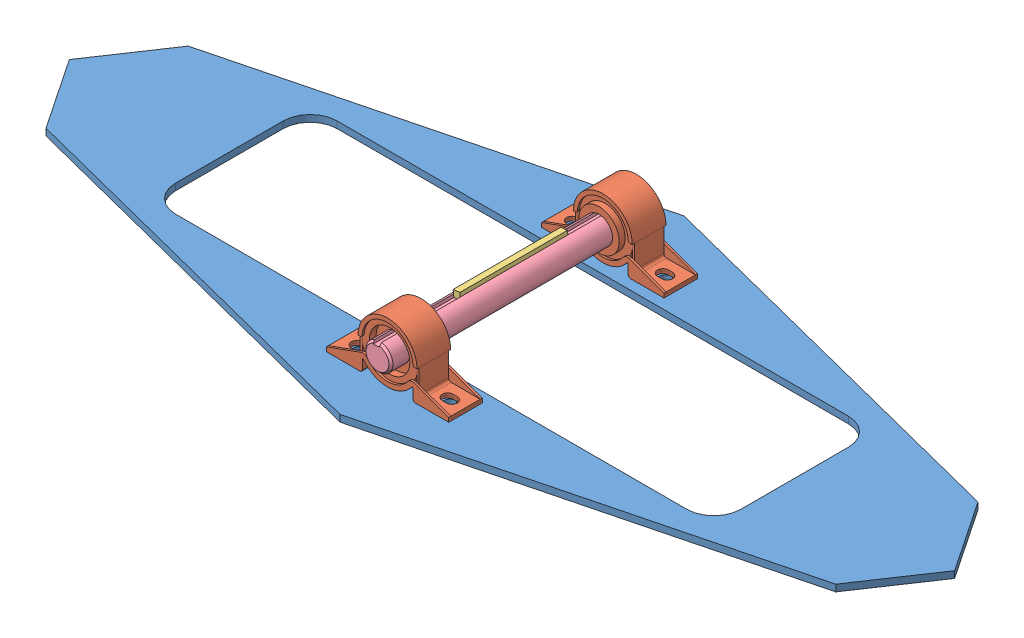
SolidWorks assembly SubAssembly_PendulumMount, configuration Default. Lengths in mm.
Overall size (835.56 62.71 324.57).
5 component instances, 4 part files, 12 mates.
Components (placement in the parent):
- Platform_Octagon_Pend-1: Platform_Octagon_Pend [Default] at origin size (835.56 6.35 324.57)
- 5913K640_LOW-PROFILE MOUNTED BALL BRNG-1: 5913K640_LOW-PROFILE MOUNTED BALL BRNG [5913K64] at (0 31.75 -101.6) size (115.49 56.36 35.32)
- Keystock-1: Keystock [Default] at (-1.2779 44.3855 0) x (0 0 1) z (-0.994925 -0.100619 0) size (101.6 6.35 6.35)
- 1497K281_FULLY KEYED 1045 STEEL DRIVE SHAFT-1: 1497K281_FULLY KEYED 1045 STEEL DRIVE SHAFT [1497K281] at (0 31.75 0) x (0 0 1) z (-0.994925 -0.100619 0) size (254 25.4 25.4)
- 5913K640_LOW-PROFILE MOUNTED BALL BRNG-2: 5913K640_LOW-PROFILE MOUNTED BALL BRNG [5913K64] at (0 31.75 101.6) x (-1 0 0) z (0 0 -1) size (115.49 56.36 35.32)
Mates (geometry in assembly coordinates):
- Coincident5: coincident anti-aligned: plane of Keystock-1 through (2.2005 41.5461 50.8) normal (0.994925 0.100619 0); plane of 1497K281_FULLY KEYED 1045 STEEL DRIVE SHAFT-1 through (1.881 44.705 -127) normal (-0.994925 -0.100619 0)
- Coincident6: coincident anti-aligned: plane of Keystock-1 through (2.2005 41.5461 50.8) normal (0.100619 -0.994925 0); plane of 1497K281_FULLY KEYED 1045 STEEL DRIVE SHAFT-1 through (-4.1173 40.9072 -127) normal (-0.100619 0.994925 0)
- Width2: width anti-aligned: plane of Keystock-1 through (-1.2779 44.3855 -50.8) normal (0 0 -1); plane of Keystock-1 through (-1.2779 44.3855 50.8) normal (0 0 1); plane of 1497K281_FULLY KEYED 1045 STEEL DRIVE SHAFT-1 through (0 31.75 127) normal (0 0 1); plane of 1497K281_FULLY KEYED 1045 STEEL DRIVE SHAFT-1 through (0 31.75 -127) normal (0 0 -1)
- Concentric1: concentric anti-aligned: cylinder of 1497K281_FULLY KEYED 1045 STEEL DRIVE SHAFT-1 through (0 31.75 127) axis (0 0 -1) radius 12.7; cylinder of 5913K640_LOW-PROFILE MOUNTED BALL BRNG-1 through (0 31.75 -109.1406) axis (0 0 1) radius 12.7
- Coincident7: coincident anti-aligned: plane of Platform_Octagon_Pend-1 through (0 3.175 0) normal (0 1 0); plane of 5913K640_LOW-PROFILE MOUNTED BALL BRNG-1 through (-57.7453 3.175 -85.725) normal (0 -1 0)
- Slot1: slot aligned: cylinder of Platform_Octagon_Pend-1 through (-42.8625 -3.175 -101.6) axis (0 1 0) radius 5.1594; cylinder of 5913K640_LOW-PROFILE MOUNTED BALL BRNG-1 through (-40.8781 3.175 -101.6) axis (0 1 0) radius 5.1594; cylinder of 5913K640_LOW-PROFILE MOUNTED BALL BRNG-1 through (-44.8469 3.175 -101.6) axis (0 1 0) radius 5.1594
- Slot2: slot aligned: cylinder of Platform_Octagon_Pend-1 through (42.8625 -3.175 -101.6) axis (0 1 0) radius 5.1594; cylinder of 5913K640_LOW-PROFILE MOUNTED BALL BRNG-1 through (40.8781 3.175 -101.6) axis (0 1 0) radius 5.1594; cylinder of 5913K640_LOW-PROFILE MOUNTED BALL BRNG-1 through (44.8469 3.175 -101.6) axis (0 1 0) radius 5.1594
- Concentric2: concentric aligned: cylinder of 1497K281_FULLY KEYED 1045 STEEL DRIVE SHAFT-1 through (0 31.75 127) axis (0 0 -1) radius 12.7; cylinder of 5913K640_LOW-PROFILE MOUNTED BALL BRNG-2 through (0 31.75 109.1406) axis (0 0 -1) radius 12.7
- Coincident8: coincident anti-aligned: plane of Platform_Octagon_Pend-1 through (0 3.175 0) normal (0 1 0); plane of 5913K640_LOW-PROFILE MOUNTED BALL BRNG-2 through (-26.0572 3.175 85.725) normal (0 -1 0)
- Slot3: slot aligned: cylinder of Platform_Octagon_Pend-1 through (-42.8625 -3.175 101.6) axis (0 1 0) radius 5.1594; cylinder of 5913K640_LOW-PROFILE MOUNTED BALL BRNG-2 through (-40.8781 3.175 101.6) axis (0 1 0) radius 5.1594; cylinder of 5913K640_LOW-PROFILE MOUNTED BALL BRNG-2 through (-44.8469 3.175 101.6) axis (0 1 0) radius 5.1594
- Slot4: slot aligned: cylinder of Platform_Octagon_Pend-1 through (42.8625 -3.175 101.6) axis (0 1 0) radius 5.1594; cylinder of 5913K640_LOW-PROFILE MOUNTED BALL BRNG-2 through (44.8469 3.175 101.6) axis (0 1 0) radius 5.1594; cylinder of 5913K640_LOW-PROFILE MOUNTED BALL BRNG-2 through (40.8781 3.175 101.6) axis (0 1 0) radius 5.1594
- Width3: width anti-aligned: plane of 1497K281_FULLY KEYED 1045 STEEL DRIVE SHAFT-1 through (0 31.75 -127) normal (0 0 -1); plane of 1497K281_FULLY KEYED 1045 STEEL DRIVE SHAFT-1 through (0 31.75 127) normal (0 0 1); plane of Platform_Octagon_Pend-1 through (241.3 -3.175 -76.2) normal (0 0 1); plane of Platform_Octagon_Pend-1 through (241.3 -3.175 76.2) normal (0 0 -1)
